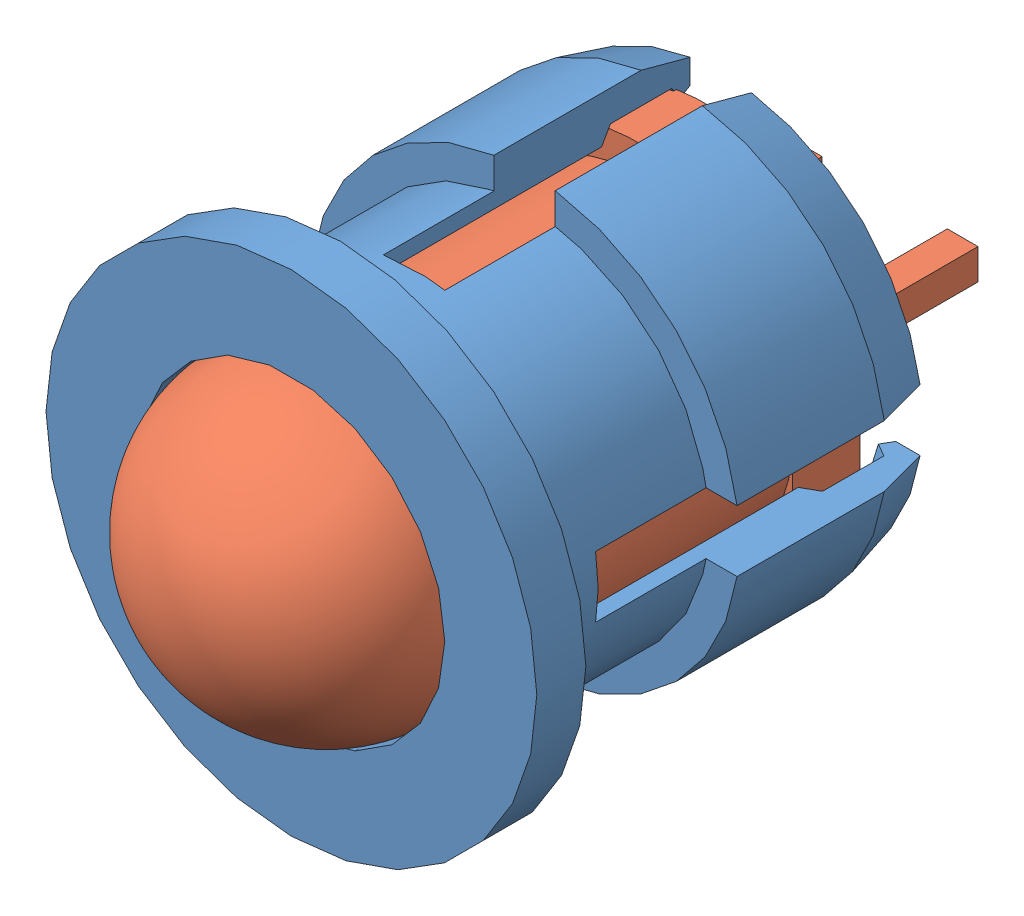
SolidWorks assembly 5mm-grommit-with-LED, configuration Default. Lengths in mm.
Overall size (8 8 11.6).
2 component instances, 2 part files, 3 mates.
Components (placement in the parent):
- 5mm LED GROMMIT-1: 5mm LED GROMMIT [Default] at origin size (8 8 7)
- Led Lamp 5 mm-1: Led Lamp 5 mm [Default] at (0 0 0.3289) x (0 0 1) z (0 1 0) size (11.6 5.45 5.9)
Mates (geometry in assembly coordinates):
- Concentric1: concentric anti-aligned: cylinder of 5mm LED GROMMIT-1 through (0 0 -20) axis (0 0 1) radius 2.5; cylinder of Led Lamp 5 mm-1 through (0 0 1.3289) axis (0 0 -1) radius 2.5
- Coincident1: coincident aligned: cone of 5mm LED GROMMIT-1 through (0 0 1.3) axis (0 0 1); circle of Led Lamp 5 mm-1
- Coincident2: coincident aligned: plane of 5mm LED GROMMIT-1 through (0 0 0) normal (0 1 0); plane of Led Lamp 5 mm-1 through (0 0 0.3289) normal (0 1 0)
